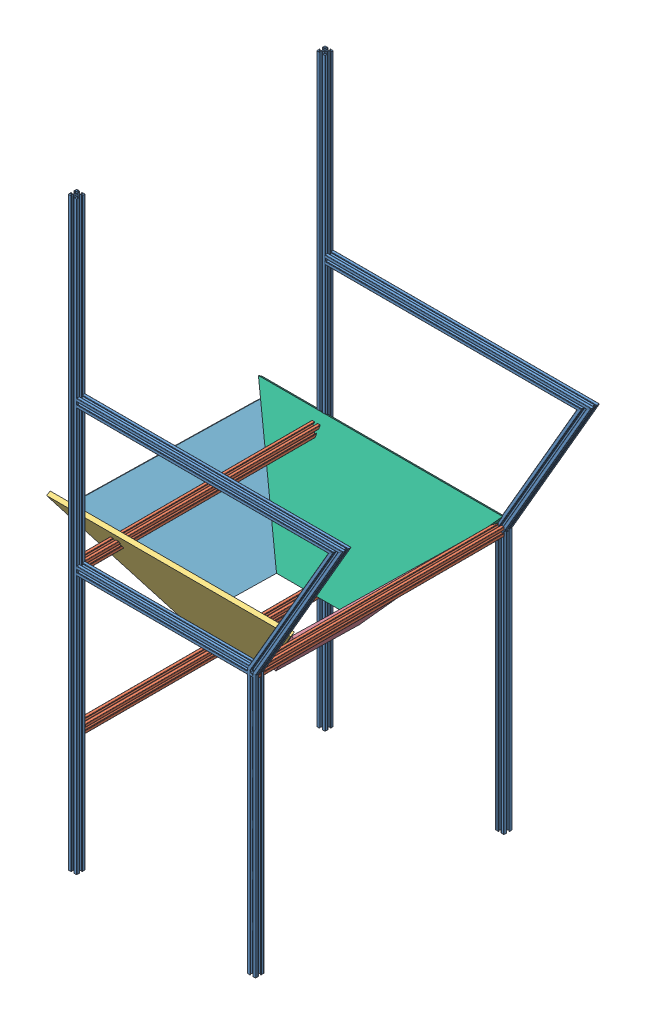
SolidWorks assembly basket rim, configuration Default. Lengths in mm.
Overall size (790.68 1390 696.81).
10 component instances, 6 part files, 11 mates.
Components (placement in the parent):
- basket-1-1: basket-1 [Default<As Machined>] at (-8.6126 1187.0681 1031.6132) size (652.36 1390 20)
- basket-1-2: basket-1 [Default<As Machined>] at (-8.6126 1187.0681 441.6132) size (652.36 1390 20)
- basket-2-1: basket-2 [Default<As Machined>] at (365.2087 489.5636 775.2532) x (0 0 -1) z (-1 0 0) size (580 20 20)
- basket-2-2: basket-2 [Default<As Machined>] at (-59.8447 492.1527 701.9732) x (0 0 1) z (0 1 0) size (580 20 20)
- basket-2-3: basket-2 [Default<As Machined>] at (-59.7305 156.5636 764.9869) x (0 0 -1) z (0.998997 -0.04478 0) size (580 20 20)
- funnel-2: funnel [Default] at (-189.6037 325.4623 286.1316) x (1 0 0) z (0 -0.512207 0.858862) size (580 458.49 537.88)
  - b-1: b [Default] at (271.4915 234.4213 462.4973) size (580 278.52 10)
  - r-1: r [Default] at (366.4915 181.5232 377.6339) x (0 -0.528981 -0.848634) z (0.771374 -0.540056 0.336634) size (460 270.37 10)
  - l-1: l [Default] at (176.4915 181.5232 377.6339) x (0 0.528981 0.848634) z (-0.771374 -0.540056 0.336634) size (460 270.37 10)
  - f-1: f [Default] at (271.4915 119.6469 288.367) x (1 0 0) z (0 0.897822 0.440358) size (580 278.52 10)
Mates (geometry in assembly coordinates):
- Coincident4: coincident: circle of assembly; point of basket-1-1; circle of basket-2-1
- Coincident5: coincident aligned: plane of basket-1-2 through (-62.0457 -133.4364 445.6132) normal (0 0 1); circle of basket-2-2
- Concentric6: concentric aligned: cylinder of basket-1-1 through (-59.7305 156.5636 1037.6132) axis (0 0 -1) radius 2.3152; circle of basket-2-3
- Concentric7: concentric aligned: cylinder of basket-1-2 through (-59.7305 156.5636 447.6132) axis (0 0 -1) radius 2.3152; circle of basket-2-3
- Concentric8: concentric anti-aligned: cylinder of basket-1-2 through (-59.8447 492.1527 451.6132) axis (0 0 -1) radius 2.201; circle of basket-2-2
- Parallel3: parallel: line of basket-1-2 through (365.2087 491.5636 441.6132) axis (-1 0 0); plane of basket-2-2 through (-56.0447 502.1527 1025.6132) normal (0 1 0)
- Coincident6: coincident aligned: plane of basket-1-1 through (375.2087 -133.4364 1027.8132) normal (1 0 0); plane of basket-2-1 through (375.2087 498.7636 451.6132) normal (1 0 0)
- Parallel4: parallel anti-aligned: cylinder of basket-1-2 through (365.2087 491.5636 441.6132) axis (0 0 -1) radius 0.9; cylinder of basket-2-1 through (365.2087 489.5636 451.6132) axis (0 0 1) radius 2
- Coincident10: coincident aligned: plane of basket-1-2 through (375.2087 -133.4364 450.8132) normal (1 0 0); plane of basket-2-1 through (375.2087 485.7636 451.6132) normal (1 0 0)
- Coincident11: coincident anti-aligned: plane of basket-1-2 through (356.0087 -133.4364 451.6132) normal (0 0 1); plane of basket-2-1 through (360.4087 491.818 451.6132) normal (0 0 -1)
- Coincident18: coincident: cylinder of basket-1-2 through (-59.7913 500.7636 450.8132) axis (1 0 0) radius 0.8; line of funnel-2 through (420.4334 501.5399 450.6199) axis (-1 0 0)
